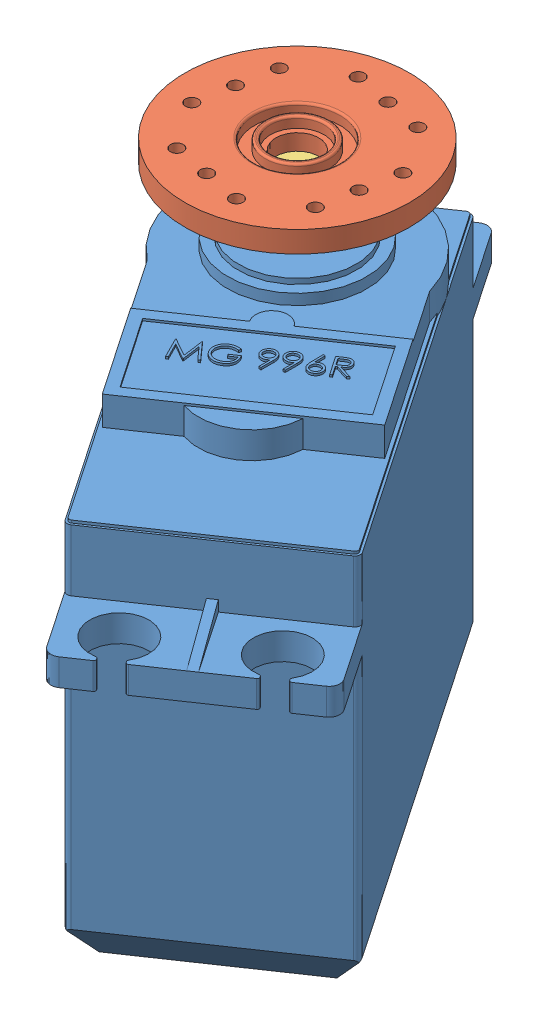
SolidWorks assembly Servo_Assembly, configuration Predeterminado. Lengths in mm.
Overall size (48.03 47.5 57.55).
3 component instances, 3 part files, 4 mates.
Components (placement in the parent):
- MG996R Servo-1: MG996R Servo [Predeterminado] at (2.2905 -18.8491 62.2691) x (0.562335 0 0.82691) z (-0.82691 0 0.562335) size (56 40 20)
- Servo_Disk-1: Servo_Disk [Predeterminado] at (-3.3329 26.6509 54) x (0.186077 0 -0.982535) z (0.982535 0 0.186077) size (21 5 21)
- Servo_Flanged Bushing-1: Servo_Flanged Bushing [Predeterminado] at (-3.3329 18.1509 54) size (4 8 4)
Mates (geometry in assembly coordinates):
- Concéntrica1: concentric aligned: cylinder of MG996R Servo-1 through (-3.3329 16.1509 54) axis (0 1 0) radius 1.75; cylinder of Servo_Disk-1 through (-3.3329 23.6509 54) axis (0 1 0) radius 4
- Distancia1: distance = 47.5 mm anti-aligned: plane of Servo_Disk-1 through (-3.3329 28.6509 54) normal (0 1 0); plane of MG996R Servo-1 through (2.2905 -18.8491 62.2691) normal (0 -1 0)
- Concéntrica2: concentric anti-aligned: cylinder of MG996R Servo-1 through (-3.3329 16.1509 54) axis (0 1 0) radius 1.75; cylinder of Servo_Flanged Bushing-1 through (-3.3329 23.1509 54) axis (0 -1 0) radius 1.75
- Distancia2: distance = 2 mm anti-aligned: plane of Servo_Flanged Bushing-1 through (-3.3329 23.1509 54) normal (0 -1 0); plane of MG996R Servo-1 through (-3.3329 21.1509 54) normal (0 1 0)
